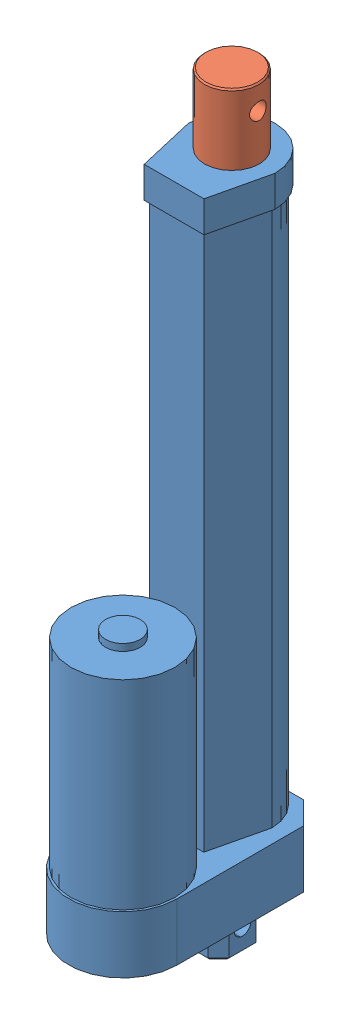
SolidWorks assembly electric150mmActuatorAssembly, configuration Default. Lengths in mm.
Overall size (39.69 274.18 75.62).
2 component instances, 2 part files, 3 mates.
Components (placement in the parent):
- electric150mmActuator-1: electric150mmActuator [Default] at (101.4524 16.1967 179.9348) x (0 -1 0) z (0 0 -1) size (248.46 39.69 75.62)
- electric150mmActuatorRod-1: electric150mmActuatorRod [Default] at (81.6086 21.2767 194.6414) size (20 228.92 20)
Mates (geometry in assembly coordinates):
- Concentric1: concentric anti-aligned: cylinder of electric150mmActuator-1 through (81.6086 21.2767 194.6414) axis (0 1 0) radius 10.0012; cylinder of electric150mmActuatorRod-1 through (81.6086 224.4767 194.6414) axis (0 -1 0) radius 10.0012
- LimitDistance1: limit distance = 25.7175 mm aligned: plane of electric150mmActuatorRod-1 through (81.6086 250.1942 194.6414) normal (0 1 0); plane of electric150mmActuator-1 through (101.4524 224.4767 179.9348) normal (0 1 0)
- Parallel1: parallel aligned: plane of electric150mmActuator-1 through (101.4524 -4.8218 179.9348) normal (1 0 0); plane of electric150mmActuatorRod-1 through (91.6099 21.2767 194.6414) normal (1 0 0)
